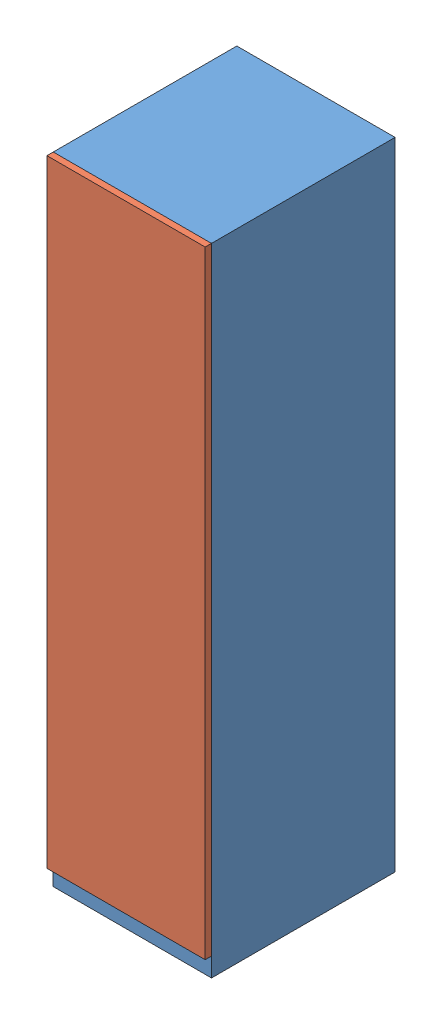
SolidWorks assembly PAX-R, configuration Standard. Lengths in mm.
Overall size (500 2010 600).
5 component instances, 5 part files, 12 mates.
Components (placement in the parent):
- Pax-Korpus-Kleiderschrank-1: Pax-Korpus-Kleiderschrank [Standard] at (-317.8358 -932.7261 1650) size (500 2010 580)
- BALLSTAD-Tür-1: BALLSTAD-Tür [Standard] at (-317.8358 102.2739 1940) size (500 1950 20)
- KOMPLIMENT-Schublade-1: KOMPLIMENT-Schublade [Standard] at (-317.8358 -702.7261 1655) size (480 160 570)
- KOMPLEMENT-Regalbode-2: KOMPLEMENT-Regalbode [Standard] at (-317.8358 -532.7261 1655) size (480 10 570)
- KOMPLEMENT-Netzdrahtkorb-1: KOMPLEMENT-Netzdrahtkorb [Standard] at (-317.8358 -712.7261 1655) size (480 160 570)
Mates (geometry in assembly coordinates):
- Deckungsgleich1: coincident anti-aligned: plane of BALLSTAD-Tür-1 through (-317.8358 102.2739 1940) normal (0 0 -1); plane of Pax-Korpus-Kleiderschrank-1 through (-567.8358 -922.7261 1940) normal (0 0 1)
- Deckungsgleich2: coincident aligned: plane of BALLSTAD-Tür-1 through (-567.8358 -872.7261 1960) normal (-1 0 0); plane of Pax-Korpus-Kleiderschrank-1 through (-567.8358 -922.7261 1940) normal (-1 0 0)
- Deckungsgleich3: coincident aligned: plane of BALLSTAD-Tür-1 through (-567.8358 1077.2739 1960) normal (0 1 0); plane of Pax-Korpus-Kleiderschrank-1 through (-317.8358 1077.2739 1650) normal (0 1 0)
- Deckungsgleich7: coincident anti-aligned: plane of Pax-Korpus-Kleiderschrank-1 through (-557.8358 1067.2739 1370) normal (0 0 1); plane of KOMPLIMENT-Schublade-1 through (-557.8358 -692.7261 1370) normal (0 0 -1)
- Deckungsgleich8: coincident: plane of Pax-Korpus-Kleiderschrank-1 through (-557.8358 1067.2739 1940) normal (1 0 0); plane of KOMPLIMENT-Schublade-1 through (-557.8358 -692.7261 1940) normal (-1 0 0)
- Deckungsgleich10: coincident anti-aligned: plane of Pax-Korpus-Kleiderschrank-1 through (-557.8358 1067.2739 1940) normal (1 0 0); plane of KOMPLEMENT-Regalbode-2 through (-557.8358 -522.7261 1940) normal (-1 0 0)
- Deckungsgleich11: coincident anti-aligned: plane of Pax-Korpus-Kleiderschrank-1 through (-557.8358 1067.2739 1370) normal (0 0 1); plane of KOMPLEMENT-Regalbode-2 through (-557.8358 -522.7261 1370) normal (0 0 -1)
- Abstand3: distance = 10 mm anti-aligned: plane of KOMPLIMENT-Schublade-1 through (-317.8358 -542.7261 1655) normal (0 1 0); plane of KOMPLEMENT-Regalbode-2 through (-317.8358 -532.7261 1655) normal (0 -1 0)
- Deckungsgleich17: coincident anti-aligned: plane of Pax-Korpus-Kleiderschrank-1 through (-317.8358 -872.7261 1650) normal (0 1 0); plane of KOMPLEMENT-Netzdrahtkorb-1 through (-317.8358 -872.7261 1655) normal (0 -1 0)
- Deckungsgleich18: coincident: plane of Pax-Korpus-Kleiderschrank-1 through (-77.8358 1067.2739 1370) normal (-1 0 0); line of KOMPLEMENT-Netzdrahtkorb-1 through (-77.8358 -712.7261 1940) axis (0 0 -1)
- Deckungsgleich19: coincident: plane of Pax-Korpus-Kleiderschrank-1 through (-557.8358 1067.2739 1370) normal (0 0 1); line of KOMPLEMENT-Netzdrahtkorb-1 through (-77.8358 -712.7261 1370) axis (-1 0 0)
- Abstand7: distance = 10 mm: plane of KOMPLEMENT-Netzdrahtkorb-1 through (-317.8358 -712.7261 1655) normal (0 1 0); plane of KOMPLIMENT-Schublade-1 through (-317.8358 -702.7261 1655) normal (0 -1 0)
